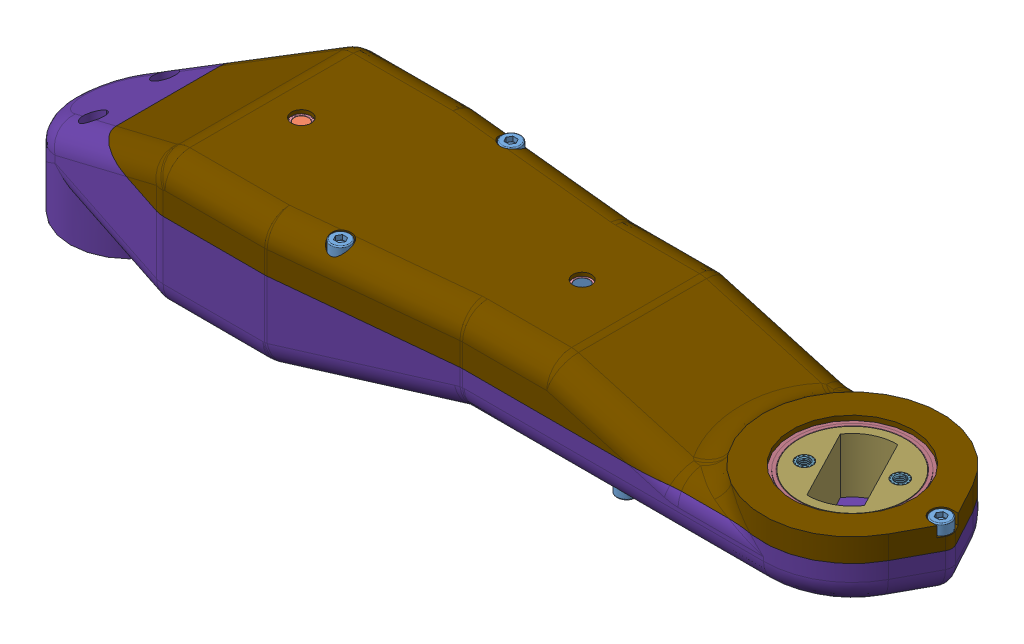
SolidWorks assembly LEG_ASSEMBLY, configuration Default. Lengths in mm.
Overall size (248 47.27 60).
52 component instances, 20 part files, 73 mates.
Components (placement in the parent):
- Actuator_Module-1: Actuator_Module [Default] at (5.9246 93.1833 215.532) size (49.6 36 49.6)
  - BLDC_Motor_5010-1: BLDC_Motor_5010 [Varsayılan] at (23.9187 12.962 41.3722) size (49.6 20 49.6)
  - MOTOR_SHAFT-1: MOTOR_SHAFT [Default] at (23.9187 28.962 41.3722) x (-0.884655 0 0.466247) z (-0.466247 0 -0.884655) size (4 36 4)
  - Gates_2GT_20T_Toothed_Pulley-1: Gates_2GT_20T_Toothed_Pulley [Výchozí] at (23.9187 27.862 41.3722) x (0.949687 0 0.313202) z (-0.313202 0 0.949687) size (15 9.4 15)
  - BEARING_MR84-2RS_4x8x2mm.step-4: BEARING_MR84-2RS_4x8x2mm.step [Default] at (23.9187 45.962 41.3722) x (-0.723388 0 -0.690442) z (0 -1 0) size (8 8 2)
  - pulley-motor-interface-1: pulley-motor-interface [Default] at (23.9187 32.962 41.3722) size (20 2.5 20)
  - bearing_spacer_1mm-1: bearing_spacer_1mm [Default] at (23.9187 43.862 41.3722) size (5.2 1 5.2)
  - socket countersunk head screw_din-1: socket countersunk head screw_din [DIN 7991 - M3 x 8 --- 4.8N] at (29.9187 34.512 41.3722) x (0 -1 0) z (0.002985 0 0.999996) size (8 5.7 5.7)
  - socket countersunk head screw_din-2: socket countersunk head screw_din [DIN 7991 - M3 x 8 --- 4.8N] at (23.9187 34.512 47.3722) x (0 -1 0) z (0.006654 0 0.999978) size (8 5.7 5.7)
  - socket countersunk head screw_din-3: socket countersunk head screw_din [DIN 7991 - M3 x 8 --- 4.8N] at (17.9187 34.512 41.3722) x (0 -1 0) z (-0.019944 0 0.999801) size (8 5.7 5.7)
  - socket countersunk head screw_din-4: socket countersunk head screw_din [DIN 7991 - M3 x 8 --- 4.8N] at (23.9187 34.512 35.3722) x (0 -1 0) z (-0.046377 0 0.998924) size (8 5.7 5.7)
- Reduction_module-1: Reduction_module [Default] at (122.5557 169.9706 256.5456) x (-0.502623 0 -0.864506) z (-0.864506 0 0.502623) size (46.5 23.1 46.5)
  - BEARING_MR84-2RS_4x8x2mm.step-2: BEARING_MR84-2RS_4x8x2mm.step [Default] at (6.5822 30.8254 12.0346) x (0.704016 0 0.710185) z (0 -1 0) size (8 8 2)
  - DRIVEN_PULLEY_FIRST_REDUCTION-1: DRIVEN_PULLEY_FIRST_REDUCTION [По умолчанию] at (6.5822 31.8754 12.0346) x (0.983912 0 0.178656) z (0 1 0) size (40 40 8.1)
  - GT2_driving_pulley_second_reduction-1: GT2_driving_pulley_second_reduction [Default] at (6.5822 37.4254 12.0346) x (0.960792 0 -0.27727) z (0 -1 0) size (16 16 16)
  - REDUCTION_SHAFT-1: REDUCTION_SHAFT [Default] at (6.5822 41.3754 12.0346) size (4 23.1 4)
  - BEARING_MR84-2RS_4x8x2mm.step-3: BEARING_MR84-2RS_4x8x2mm.step [Default] at (6.5822 51.9254 12.0346) x (-0.641213 0 -0.767363) z (0 -1 0) size (8 8 2)
  - bearing_spacer_1mm-1: bearing_spacer_1mm [Default] at (6.5822 31.8254 12.0346) x (0.908927 0 0.416955) z (-0.416955 0 0.908927) size (5.2 1 5.2)
  - bearing_spacer_1mm-2: bearing_spacer_1mm [Default] at (6.5822 49.9254 12.0346) size (5.2 1 5.2)
- Encoder_magnet-1: Encoder_magnet [Default] at (29.8433 102.6453 256.9041) x (0.937581 0 0.347767) z (-0.347767 0 0.937581) size (4 1.5 4)
- Second_reduction_module-1: Second_reduction_module [Default] at (151.6287 143.091 264.4791) x (0.460617 0 0.887599) z (0.887599 0 -0.460617) size (37.7 15.5 37.7)
  - DRIVEN_PULLEY_SECOND_REDUCTION-1: DRIVEN_PULLEY_SECOND_REDUCTION [По умолчанию] at (8.5756 23.3079 32.9704) x (-1 0 0) z (0 -1 0) size (37.7 37.7 15.5)
  - Bearings_6706-2RS.stp-1: Bearings_6706-2RS.stp [Default] at (8.5756 23.7518 32.9704) x (0 1 0) z (0 0 -1) size (3.99 37.01 37.01)
  - Bearings_6706-2RS.stp-2: Bearings_6706-2RS.stp [Default] at (8.5756 12.264 32.9704) x (0 1 0) z (0 0 1) size (3.99 37.01 37.01)
  - M3_INSERT.step-1: M3_INSERT.step [Default] at (8.5756 10.2579 42.9704) size (4.52 4 4.53)
  - M3_INSERT.step-2: M3_INSERT.step [Default] at (8.5756 10.2579 22.9704) size (4.52 4 4.53)
- ENCODER_HOUSING-1: ENCODER_HOUSING [Default] at (29.8433 97.6453 256.9041) x (-1 0 0) z (0 0 1) size (36.04 6.5 36.04)
- M3_INSERT.step-2: M3_INSERT.step [Default] at (41.8633 100.1453 268.9241) x (0.990313 0 -0.138851) z (0.138851 0 0.990313) size (4.52 4 4.53)
- M3_INSERT.step-3: M3_INSERT.step [Default] at (17.8233 100.1453 268.9241) x (-0.211556 0 -0.977366) z (0.977366 0 -0.211556) size (4.52 4 4.53)
- M3_INSERT.step-4: M3_INSERT.step [Default] at (41.8633 100.1453 244.8841) x (0.848747 0 -0.5288) z (0.5288 0 0.848747) size (4.52 4 4.53)
- M3_INSERT.step-5: M3_INSERT.step [Default] at (17.8233 100.1453 244.8841) x (0.728724 0 -0.684808) z (0.684808 0 0.728724) size (4.52 4 4.53)
- encoder_TLE5012-1: encoder_TLE5012 [Default] at (29.8433 98.6453 256.9041) size (30.04 2.5 30.04)
- LEG_MODULE_BOTTOM-1: LEG_MODULE_BOTTOM [Default] at (29.8433 122.6453 256.9041) x (1 0 0) z (0 0 -1) size (248 33.55 60)
- LEG_MODULE_TOP-1: LEG_MODULE_TOP [Default] at (29.8433 122.6453 256.9041) x (1 0 0) z (0 0 -1) size (220.5 13.77 60)
- M3_INSERT.step-6: M3_INSERT.step [Default] at (141.8433 127.6453 236.4041) size (4.52 4 4.53)
- M3_INSERT.step-7: M3_INSERT.step [Default] at (141.8433 127.6453 277.4041) size (4.52 4 4.53)
- M3_INSERT.step-8: M3_INSERT.step [Default] at (64.8433 127.6453 280.8817) x (1 0 0) z (0 0 -1) size (4.52 4 4.53)
- M3_INSERT.step-9: M3_INSERT.step [Default] at (64.8433 127.6453 232.9266) x (1 0 0) z (0 0 -1) size (4.52 4 4.53)
- M3_INSERT.step-10: M3_INSERT.step [Default] at (209.8433 127.6453 256.9041) x (0.998959 0 0.045621) z (0.045621 0 -0.998959) size (4.52 4 4.53)
- socket head cap screw_din-3: socket head cap screw_din [DIN 912 M3 x 12 --- 12N] at (141.8433 116.0453 236.4041) x (0 1 0) z (0 0 1) size (15 5.5 5.5)
- socket head cap screw_din-4: socket head cap screw_din [DIN 912 M3 x 12 --- 12N] at (141.8433 116.0453 277.4041) x (0 1 0) z (0 0 1) size (15 5.5 5.5)
- socket head cap screw_din-5: socket head cap screw_din [DIN 912 M3 x 10 --- 10N] at (209.8433 134.1453 256.9041) x (0 -1 0) z (0 0 1) size (13 5.5 5.5)
- socket head cap screw_din-6: socket head cap screw_din [DIN 912 M3 x 16 --- 16N] at (64.8433 141.1453 280.8817) x (0 -1 0) z (0 0 1) size (19 5.5 5.5)
- socket head cap screw_din-8: socket head cap screw_din [DIN 912 M3 x 16 --- 16N] at (64.8433 141.1453 232.9266) x (0 -1 0) z (0 0 1) size (19 5.5 5.5)
- socket countersunk head screw_din-2: socket countersunk head screw_din [DIN 7991 - M3 x 8 --- 4.8N] at (29.8433 104.0953 247.4041) x (0 1 0) z (-0.007855 0 0.999969) size (8 5.7 5.7)
- socket countersunk head screw_din-3: socket countersunk head screw_din [DIN 7991 - M3 x 8 --- 4.8N] at (37.8433 104.0953 256.9041) x (0 1 0) z (0.008136 0 0.999967) size (8 5.7 5.7)
- socket countersunk head screw_din-4: socket countersunk head screw_din [DIN 7991 - M3 x 8 --- 4.8N] at (21.8433 104.0953 256.9041) x (0 1 0) z (0.007396 0 0.999973) size (8 5.7 5.7)
- socket countersunk head screw_din-5: socket countersunk head screw_din [DIN 7991 - M3 x 8 --- 4.8N] at (29.8433 104.0953 266.4041) x (0 1 0) z (0.005455 0 0.999985) size (8 5.7 5.7)
- socket countersunk head screw_din-7: socket countersunk head screw_din [DIN 7991 - M3 x 8 --- 4.8N] at (17.7811 97.5953 244.7865) x (0 1 0) z (-0.03444 0 0.999407) size (8 5.7 5.7)
- socket countersunk head screw_din-8: socket countersunk head screw_din [DIN 7991 - M3 x 8 --- 4.8N] at (17.7988 97.5953 268.9386) x (0 1 0) z (-0.029949 0 0.999551) size (8 5.7 5.7)
- socket countersunk head screw_din-9: socket countersunk head screw_din [DIN 7991 - M3 x 8 --- 4.8N] at (41.8812 97.5953 268.9381) x (0 1 0) z (0.000234 0 1) size (8 5.7 5.7)
- socket countersunk head screw_din-10: socket countersunk head screw_din [DIN 7991 - M3 x 8 --- 4.8N] at (41.8891 97.5953 244.8529) x (0 1 0) z (-0.035147 0 0.999382) size (8 5.7 5.7)
Mates (geometry in assembly coordinates):
- Concentric1: concentric anti-aligned: cylinder of LEG_MODULE-1 through (37.3811 115.9942 237.8663) axis (0 1 0) radius 2.75; cylinder of Actuator_Module-1/MOTOR_SHAFT-1 through (29.8433 140.1453 256.9041) axis (0 -1 0) radius 2
- Concentric3: concentric aligned: cylinder of LEG_MODULE-1 through (29.3811 125.9942 237.8663) axis (0 -1 0) radius 1.7; cylinder of Actuator_Module-1/BLDC_Motor_5010-1 through (29.3811 131.4942 237.8663) axis (0 -1 0) radius 1.5
- Coincident1: coincident anti-aligned: plane of LEG_MODULE-1 through (57.3811 127.9942 267.8663) normal (0 1 0); plane of Actuator_Module-1/BLDC_Motor_5010-1 through (29.8433 106.1453 256.9041) normal (0 -1 0)
- Coincident2: coincident anti-aligned: plane of Actuator_Module-1/MOTOR_SHAFT-1 through (29.8433 104.1453 256.9041) normal (0 -1 0); circle of Encoder_magnet-1
- Concentric4: concentric anti-aligned: cylinder of LEG_MODULE-1 through (37.3811 115.9942 237.8663) axis (0 1 0) radius 2.75; cylinder of Encoder_magnet-1 through (29.8433 104.1453 256.9041) axis (0 -1 0) radius 2
- Coincident3: coincident anti-aligned: plane of LEG_MODULE-1 through (192.3811 139.1942 237.8663) normal (0 1 0); plane of Second_reduction_module-1/Bearings_6706-2RS.stp-1 through (184.8433 117.3453 256.9041) normal (0 -1 0)
- Concentric8: concentric anti-aligned: cylinder of LEG_MODULE-1 through (192.3811 139.1942 237.8663) axis (0 1 0) radius 18.5; cylinder of Second_reduction_module-1/Bearings_6706-2RS.stp-1 through (184.8433 121.5324 256.9041) axis (0 -1 0) radius 18.5039
- Coincident5: coincident anti-aligned: plane of LEG_MODULE-1 through (57.3811 161.9942 267.8663) normal (0 -1 0); plane of Reduction_module-1/BEARING_MR84-2RS_4x8x2mm.step-2 through (107.8366 140.1453 260.7754) normal (0 1 0)
- Concentric22: concentric anti-aligned: cylinder of LEG_MODULE-1 through (116.3811 174.3079 237.8663) axis (0 -1 0) radius 4; cylinder of Reduction_module-1/BEARING_MR84-2RS_4x8x2mm.step-2 through (108.8433 156.6453 256.9041) axis (0 1 0) radius 4
- Concentric23: concentric aligned: cylinder of LEG_MODULE-1 through (25.3611 129.9942 225.8463) axis (0 -1 0) radius 2.25; cylinder of encoder_TLE5012-1 through (17.8233 100.1453 244.8841) axis (0 -1 0) radius 1.55
- Concentric24: concentric aligned: cylinder of LEG_MODULE-1 through (49.4011 129.9942 225.8463) axis (0 -1 0) radius 2.25; cylinder of encoder_TLE5012-1 through (41.8633 100.1453 244.8841) axis (0 -1 0) radius 1.55
- Concentric25: concentric aligned: cylinder of LEG_MODULE-1 through (49.4011 129.9942 225.8463) axis (0 -1 0) radius 2.25; cylinder of M3_INSERT.step-4 through (41.8633 100.1453 244.8841) axis (0 -1 0) radius 1.85
- Concentric26: concentric aligned: cylinder of LEG_MODULE-1 through (49.4011 129.9942 249.8863) axis (0 -1 0) radius 2.25; cylinder of M3_INSERT.step-2 through (41.8633 100.1453 268.9241) axis (0 -1 0) radius 1.85
- Concentric27: concentric aligned: cylinder of LEG_MODULE-1 through (25.3611 129.9942 249.8863) axis (0 -1 0) radius 2.25; cylinder of M3_INSERT.step-3 through (17.8233 100.1453 268.9241) axis (0 -1 0) radius 1.85
- Concentric28: concentric aligned: cylinder of LEG_MODULE-1 through (25.3611 129.9942 225.8463) axis (0 -1 0) radius 2.25; cylinder of M3_INSERT.step-5 through (17.8233 100.1453 244.8841) axis (0 -1 0) radius 1.85
- Coincident30: coincident anti-aligned: plane of ENCODER_HOUSING-1 through (29.8433 98.6453 256.9041) normal (0 1 0); plane of encoder_TLE5012-1 through (29.8433 98.6453 256.9041) normal (0 -1 0)
- Concentric29: concentric aligned: cylinder of ENCODER_HOUSING-1 through (41.8633 98.6453 268.9241) axis (0 -1 0) radius 6; cylinder of encoder_TLE5012-1 through (41.8633 100.1453 268.9241) axis (0 -1 0) radius 1.55
- Concentric30: concentric aligned: cylinder of ENCODER_HOUSING-1 through (41.8633 98.6453 244.8841) axis (0 -1 0) radius 6; cylinder of encoder_TLE5012-1 through (41.8633 100.1453 244.8841) axis (0 -1 0) radius 3
- Coincident31: coincident aligned: plane of LEG_MODULE-1 through (25.3611 121.9942 249.8863) normal (0 -1 0); plane of M3_INSERT.step-3 through (17.8233 100.1453 268.9241) normal (0 -1 0)
- Coincident32: coincident aligned: plane of LEG_MODULE-1 through (25.3611 121.9942 225.8463) normal (0 -1 0); plane of M3_INSERT.step-5 through (17.8233 100.1453 244.8841) normal (0 -1 0)
- Coincident33: coincident aligned: plane of LEG_MODULE-1 through (49.4011 121.9942 225.8463) normal (0 -1 0); plane of M3_INSERT.step-4 through (41.8633 100.1453 244.8841) normal (0 -1 0)
- Coincident34: coincident aligned: plane of LEG_MODULE-1 through (49.4011 121.9942 249.8863) normal (0 -1 0); plane of M3_INSERT.step-2 through (41.8633 100.1453 268.9241) normal (0 -1 0)
- Coincident35: coincident anti-aligned: plane of LEG_MODULE-1 through (49.4011 121.9942 225.8463) normal (0 -1 0); plane of encoder_TLE5012-1 through (29.8433 100.1453 256.9041) normal (0 1 0)
- Concentric31: concentric aligned: cylinder of Actuator_Module-1/MOTOR_SHAFT-1 through (29.8433 140.1453 256.9041) axis (0 -1 0) radius 2; cylinder of Encoder_magnet-1 through (29.8433 104.1453 256.9041) axis (0 -1 0) radius 2
- Coincident36: coincident anti-aligned: plane of Actuator_Module-1/BLDC_Motor_5010-1 through (29.8433 106.1453 256.9041) normal (0 -1 0); plane of LEG_MODULE_BOTTOM-1 through (49.8433 106.1453 286.9041) normal (0 1 0)
- Concentric32: concentric aligned: cylinder of Actuator_Module-1/BLDC_Motor_5010-1 through (29.8433 112.1453 247.4041) axis (0 -1 0) radius 1.5; cylinder of LEG_MODULE_BOTTOM-1 through (29.8433 104.1453 247.4041) axis (0 -1 0) radius 1.7
- Concentric33: concentric aligned: cylinder of Actuator_Module-1/BLDC_Motor_5010-1 through (29.8433 112.1453 266.4041) axis (0 -1 0) radius 1.5; cylinder of LEG_MODULE_BOTTOM-1 through (29.8433 104.1453 266.4041) axis (0 -1 0) radius 1.7
- Concentric34: concentric aligned: cylinder of M3_INSERT.step-4 through (41.8633 100.1453 244.8841) axis (0 -1 0) radius 1.85; cylinder of LEG_MODULE_BOTTOM-1 through (41.8633 108.1453 244.8841) axis (0 -1 0) radius 2.25
- Coincident37: coincident aligned: plane of M3_INSERT.step-4 through (41.8633 100.1453 244.8841) normal (0 -1 0); plane of LEG_MODULE_BOTTOM-1 through (41.8633 100.1453 244.8841) normal (0 -1 0)
- Concentric35: concentric aligned: cylinder of M3_INSERT.step-5 through (17.8233 100.1453 244.8841) axis (0 -1 0) radius 1.85; cylinder of LEG_MODULE_BOTTOM-1 through (17.8233 108.1453 244.8841) axis (0 -1 0) radius 2.25
- Coincident38: coincident aligned: plane of M3_INSERT.step-5 through (17.8233 100.1453 244.8841) normal (0 -1 0); plane of LEG_MODULE_BOTTOM-1 through (17.8233 100.1453 244.8841) normal (0 -1 0)
- Concentric36: concentric aligned: cylinder of M3_INSERT.step-2 through (41.8633 100.1453 268.9241) axis (0 -1 0) radius 1.85; cylinder of LEG_MODULE_BOTTOM-1 through (41.8633 108.1453 268.9241) axis (0 -1 0) radius 2.25
- Coincident39: coincident aligned: plane of M3_INSERT.step-2 through (41.8633 100.1453 268.9241) normal (0 -1 0); plane of LEG_MODULE_BOTTOM-1 through (41.8633 100.1453 268.9241) normal (0 -1 0)
- Concentric37: concentric aligned: cylinder of M3_INSERT.step-3 through (17.8233 100.1453 268.9241) axis (0 -1 0) radius 1.85; cylinder of LEG_MODULE_BOTTOM-1 through (17.8233 108.1453 268.9241) axis (0 -1 0) radius 2.25
- Coincident40: coincident aligned: plane of M3_INSERT.step-3 through (17.8233 100.1453 268.9241) normal (0 -1 0); plane of LEG_MODULE_BOTTOM-1 through (17.8233 100.1453 268.9241) normal (0 -1 0)
- Coincident41: coincident anti-aligned: plane of encoder_TLE5012-1 through (29.8433 100.1453 256.9041) normal (0 1 0); plane of LEG_MODULE_BOTTOM-1 through (17.8233 100.1453 244.8841) normal (0 -1 0)
- Concentric38: concentric anti-aligned: cylinder of encoder_TLE5012-1 through (17.8233 100.1453 244.8841) axis (0 -1 0) radius 1.55; cylinder of LEG_MODULE_BOTTOM-1 through (17.8233 100.1453 244.8841) axis (0 1 0) radius 3.75
- Concentric39: concentric anti-aligned: cylinder of encoder_TLE5012-1 through (41.8633 100.1453 268.9241) axis (0 -1 0) radius 1.55; cylinder of LEG_MODULE_BOTTOM-1 through (41.8633 100.1453 268.9241) axis (0 1 0) radius 3.75
- Concentric40: concentric anti-aligned: cylinder of Reduction_module-1/BEARING_MR84-2RS_4x8x2mm.step-3 through (108.8433 135.5453 256.9041) axis (0 1 0) radius 4; cylinder of LEG_MODULE_BOTTOM-1 through (108.8433 152.459 256.9041) axis (0 -1 0) radius 4
- Coincident42: coincident anti-aligned: plane of Reduction_module-1/BEARING_MR84-2RS_4x8x2mm.step-3 through (109.5179 117.0453 252.9614) normal (0 -1 0); plane of LEG_MODULE_BOTTOM-1 through (29.8433 117.0453 256.9041) normal (0 1 0)
- Concentric41: concentric anti-aligned: cylinder of Second_reduction_module-1/Bearings_6706-2RS.stp-1 through (184.8433 121.5324 256.9041) axis (0 -1 0) radius 18.5039; cylinder of LEG_MODULE_BOTTOM-1 through (184.8433 117.3453 256.9041) axis (0 1 0) radius 18.5
- Coincident43: coincident anti-aligned: plane of Second_reduction_module-1/Bearings_6706-2RS.stp-1 through (184.8433 117.3453 256.9041) normal (0 -1 0); plane of LEG_MODULE_BOTTOM-1 through (184.8433 117.3453 256.9041) normal (0 1 0)
- Concentric42: concentric aligned: cylinder of LEG_MODULE_BOTTOM-1 through (209.8433 123.6453 256.9041) axis (0 1 0) radius 2.25; cylinder of M3_INSERT.step-10 through (209.8433 127.6453 256.9041) axis (0 1 0) radius 1.85
- Coincident44: coincident aligned: plane of LEG_MODULE_BOTTOM-1 through (29.8433 127.6453 256.9041) normal (0 1 0); plane of M3_INSERT.step-10 through (209.8433 127.6453 256.9041) normal (0 1 0)
- Concentric43: concentric aligned: cylinder of LEG_MODULE_BOTTOM-1 through (64.8433 123.6453 280.8817) axis (0 1 0) radius 2.25; cylinder of M3_INSERT.step-8 through (64.8433 127.6453 280.8817) axis (0 1 0) radius 1.85
- Coincident45: coincident aligned: plane of LEG_MODULE_BOTTOM-1 through (29.8433 127.6453 256.9041) normal (0 1 0); plane of M3_INSERT.step-8 through (64.8433 127.6453 280.8817) normal (0 1 0)
- Coincident46: coincident aligned: plane of LEG_MODULE_BOTTOM-1 through (29.8433 127.6453 256.9041) normal (0 1 0); plane of M3_INSERT.step-9 through (64.8433 127.6453 232.9266) normal (0 1 0)
- Concentric45: concentric aligned: cylinder of LEG_MODULE_BOTTOM-1 through (64.8433 123.6453 232.9266) axis (0 1 0) radius 2.25; cylinder of M3_INSERT.step-9 through (64.8433 127.6453 232.9266) axis (0 1 0) radius 1.85
- Concentric46: concentric aligned: cylinder of LEG_MODULE_TOP-1 through (141.8433 131.6453 236.4041) axis (0 -1 0) radius 2.25; cylinder of M3_INSERT.step-6 through (141.8433 127.6453 236.4041) axis (0 -1 0) radius 1.85
- Coincident47: coincident aligned: plane of LEG_MODULE_TOP-1 through (64.8433 127.6453 280.8817) normal (0 -1 0); plane of M3_INSERT.step-6 through (141.8433 127.6453 236.4041) normal (0 -1 0)
- Concentric47: concentric aligned: cylinder of LEG_MODULE_TOP-1 through (141.8433 131.6453 277.4041) axis (0 -1 0) radius 2.25; cylinder of M3_INSERT.step-7 through (141.8433 127.6453 277.4041) axis (0 -1 0) radius 1.85
- Coincident48: coincident aligned: plane of LEG_MODULE_TOP-1 through (64.8433 127.6453 280.8817) normal (0 -1 0); plane of M3_INSERT.step-7 through (141.8433 127.6453 277.4041) normal (0 -1 0)
- Concentric48: concentric aligned: cylinder of LEG_MODULE_BOTTOM-1 through (64.8433 100.05 280.8817) axis (0 1 0) radius 3.5; cylinder of LEG_MODULE_TOP-1 through (64.8433 100.05 280.8817) axis (0 1 0) radius 3.5
- Coincident49: coincident anti-aligned: plane of LEG_MODULE_BOTTOM-1 through (29.8433 127.6453 256.9041) normal (0 1 0); plane of LEG_MODULE_TOP-1 through (64.8433 127.6453 280.8817) normal (0 -1 0)
- Concentric49: concentric aligned: cylinder of LEG_MODULE_BOTTOM-1 through (209.8433 123.6453 256.9041) axis (0 1 0) radius 2.25; cylinder of LEG_MODULE_TOP-1 through (209.8433 121.6453 256.9041) axis (0 1 0) radius 1.55
- Concentric51: concentric aligned: cylinder of LEG_MODULE_BOTTOM-1 through (141.8433 133.6453 236.4041) axis (0 -1 0) radius 1.55; cylinder of socket head cap screw_din-3 through (141.8433 84.2953 236.4041) axis (0 -1 0) radius 2.75
- Coincident50: coincident anti-aligned: plane of LEG_MODULE_BOTTOM-1 through (141.8433 119.0453 236.4041) normal (0 -1 0); plane of socket head cap screw_din-3 through (139.0933 119.0453 236.4041) normal (0 1 0)
- Concentric52: concentric aligned: cylinder of LEG_MODULE_BOTTOM-1 through (141.8433 133.6453 277.4041) axis (0 -1 0) radius 1.55; cylinder of socket head cap screw_din-4 through (141.8433 84.2953 277.4041) axis (0 -1 0) radius 2.75
- Coincident51: coincident anti-aligned: plane of LEG_MODULE_BOTTOM-1 through (141.8433 119.0453 277.4041) normal (0 -1 0); plane of socket head cap screw_din-4 through (139.0933 119.0453 277.4041) normal (0 1 0)
- Concentric53: concentric aligned: cylinder of LEG_MODULE_TOP-1 through (209.8433 121.6453 256.9041) axis (0 1 0) radius 1.55; cylinder of socket head cap screw_din-5 through (209.8433 165.8953 256.9041) axis (0 1 0) radius 2.75
- Coincident52: coincident anti-aligned: plane of LEG_MODULE_TOP-1 through (29.8433 131.1453 256.9041) normal (0 1 0); plane of socket head cap screw_din-5 through (212.5933 131.1453 256.9041) normal (0 -1 0)
- Concentric54: concentric aligned: cylinder of LEG_MODULE_TOP-1 through (64.8433 138.1453 280.8817) axis (0 1 0) radius 3; cylinder of socket head cap screw_din-6 through (64.8433 172.8953 280.8817) axis (0 1 0) radius 2.75
- Coincident53: coincident anti-aligned: plane of LEG_MODULE_TOP-1 through (64.8433 138.1453 280.8817) normal (0 1 0); plane of socket head cap screw_din-6 through (67.5933 138.1453 280.8817) normal (0 -1 0)
- Concentric56: concentric anti-aligned: cylinder of LEG_MODULE_TOP-1 through (64.8433 141.1454 232.9266) axis (0 -1 0) radius 1.55; cylinder of socket head cap screw_din-8 through (64.8433 172.8953 232.9266) axis (0 1 0) radius 2.75
- Coincident54: coincident anti-aligned: plane of LEG_MODULE_TOP-1 through (64.8433 138.1453 232.9266) normal (0 1 0); plane of socket head cap screw_din-8 through (67.5933 138.1453 232.9266) normal (0 -1 0)
- Coincident55: coincident aligned: cone of LEG_MODULE_BOTTOM-1 through (29.8433 104.1453 247.4041) axis (0 1 0); cylinder of socket countersunk head screw_din-2 through (29.8433 104.4453 247.4041) axis (0 1 0) radius 785.3982
- Coincident56: coincident aligned: cylinder of LEG_MODULE_BOTTOM-1 through (37.8433 104.1453 256.9041) axis (0 1 0) radius 785.3982; cylinder of socket countersunk head screw_din-3 through (37.8433 104.4453 256.9041) axis (0 1 0) radius 785.3982
- Coincident57: coincident aligned: cylinder of LEG_MODULE_BOTTOM-1 through (21.8433 104.1453 256.9041) axis (0 1 0) radius 785.3982; cylinder of socket countersunk head screw_din-4 through (21.8433 104.4453 256.9041) axis (0 1 0) radius 785.3982
- Coincident58: coincident aligned: cylinder of LEG_MODULE_BOTTOM-1 through (29.8433 104.1453 266.4041) axis (0 1 0) radius 785.3982; cylinder of socket countersunk head screw_din-5 through (29.8433 104.4453 266.4041) axis (0 1 0) radius 785.3982
- Coincident59: coincident aligned: cylinder of ENCODER_HOUSING-1 through (17.7811 97.6453 244.7865) axis (0 1 0) radius 785.3982; cylinder of socket countersunk head screw_din-7 through (17.7811 97.9453 244.7865) axis (0 1 0) radius 785.3982
- Coincident60: coincident aligned: cylinder of ENCODER_HOUSING-1 through (17.7988 97.6453 268.9386) axis (0 1 0) radius 785.3982; cylinder of socket countersunk head screw_din-8 through (17.7988 97.9453 268.9386) axis (0 1 0) radius 785.3982
- Coincident61: coincident aligned: cylinder of ENCODER_HOUSING-1 through (41.8812 97.6453 268.9381) axis (0 1 0) radius 785.3982; cylinder of socket countersunk head screw_din-9 through (41.8812 97.9453 268.9381) axis (0 1 0) radius 785.3982
- Coincident62: coincident aligned: cylinder of ENCODER_HOUSING-1 through (41.8891 97.6453 244.8529) axis (0 1 0) radius 785.3982; cylinder of socket countersunk head screw_din-10 through (41.8891 97.9453 244.8529) axis (0 1 0) radius 785.3982
